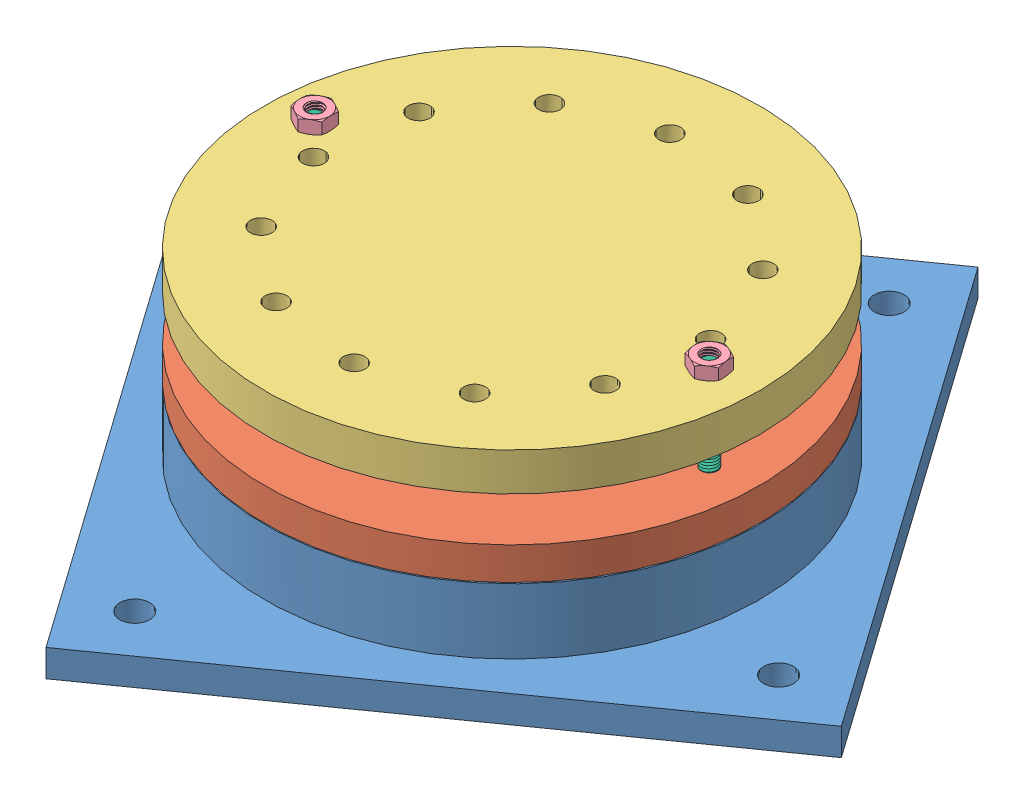
SolidWorks assembly bay con 12 mk2, configuration Default. Lengths in mm.
Overall size (146.35 41.21 146.35).
8 component instances, 6 part files, 0 mates.
Components (placement in the parent):
- bayonet container 12-1: bayonet container 12 [Default] at (187.5344 -18.4393 137.5684) x (-0.577172 0 -0.816622) z (0.816622 0 -0.577172) size (105 17 105)
- inner bayonet connector 12-1: inner bayonet connector 12 [Default] at (187.5344 4.7545 137.5684) x (-0.648407 0 0.761294) z (0 -1 0) size (91 91 15.15)
- bay container 12 bottom-1: bay container 12 bottom [Default] at (187.5344 19.8745 137.5684) x (-0.398589 0 0.917129) z (0.917129 0 0.398589) size (91 9 91)
- m3 nut-1: m3 nut [Default] at (149.7622 21.4745 136.1186) x (0.536216 0 0.844081) z (-0.844081 0 0.536216) size (5.5 2.58 6.35)
- m3 nut-2: m3 nut [Default] at (225.3065 21.4745 139.0181) x (-0.993076 0 0.117477) z (-0.117477 0 -0.993076) size (5.5 2.58 6.35)
- 8mm length spring-1: 8mm length spring [Default] at (187.5344 5.1452 137.5684) x (1 0 0.000002) z (-0.000002 0 1) size (15.24 7.69 15.24)
- M3 25MM-1: M3 25MM [Default] at (149.7622 21.5607 136.1186) x (0.844081 0 -0.536216) z (0 -1 0) size (6 6 27.96)
- M3 25MM-2: M3 25MM [Default] at (225.3065 21.5607 139.0181) x (-0.918767 0 -0.394799) z (0 -1 0) size (6 6 27.96)
